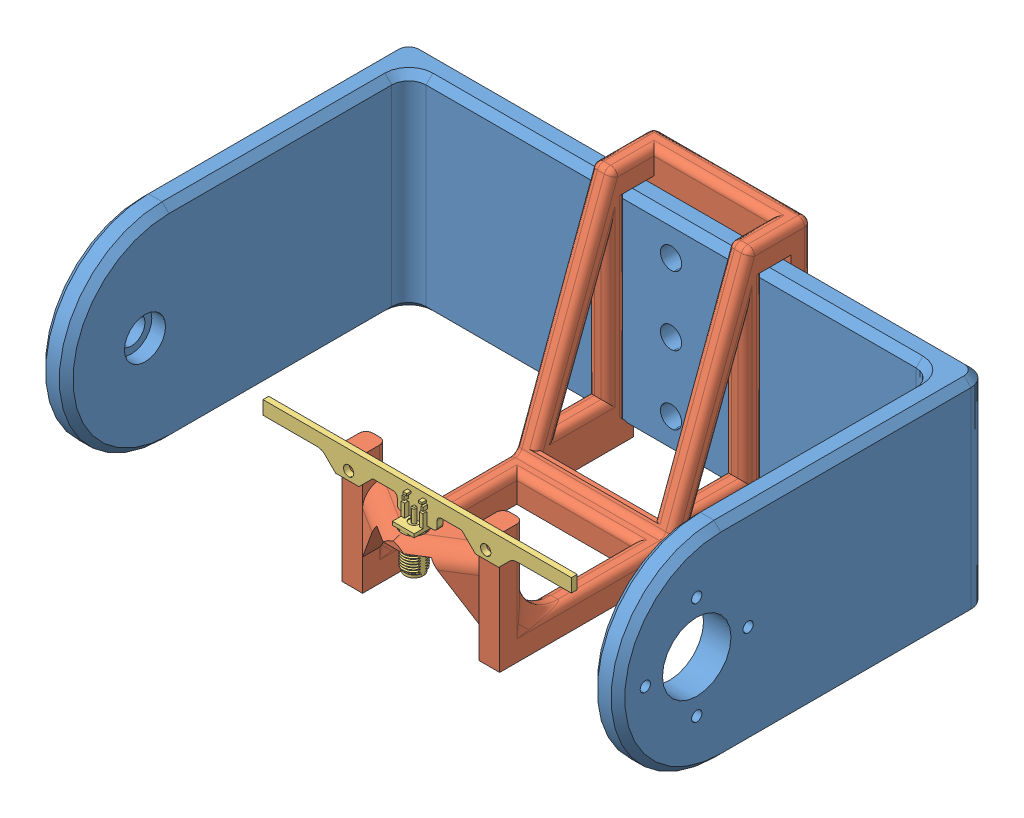
SolidWorks assembly Gemini_V3_Dipole_Holder, configuration Default. Lengths in mm.
Overall size (170.5 70 114.15).
3 component instances, 3 part files, 0 mates.
Components (placement in the parent):
- DUT_Bridge-1: DUT_Bridge [Default] at (0 0 -85) x (1 0 0) z (0 -1 0) size (170.5 108 60)
- gemini_v3_Dipole_holder-1: gemini_v3_Dipole_holder [Default] at (3.85 -162.8742 -55.1496) x (0 0 -1) z (1 0 0) size (99 70 46.36)
- Dipole_1700MHz-1: Dipole_1700MHz [Default] at (4.0217 -5.2061 1.0918) size (90 20.38 6.64)
